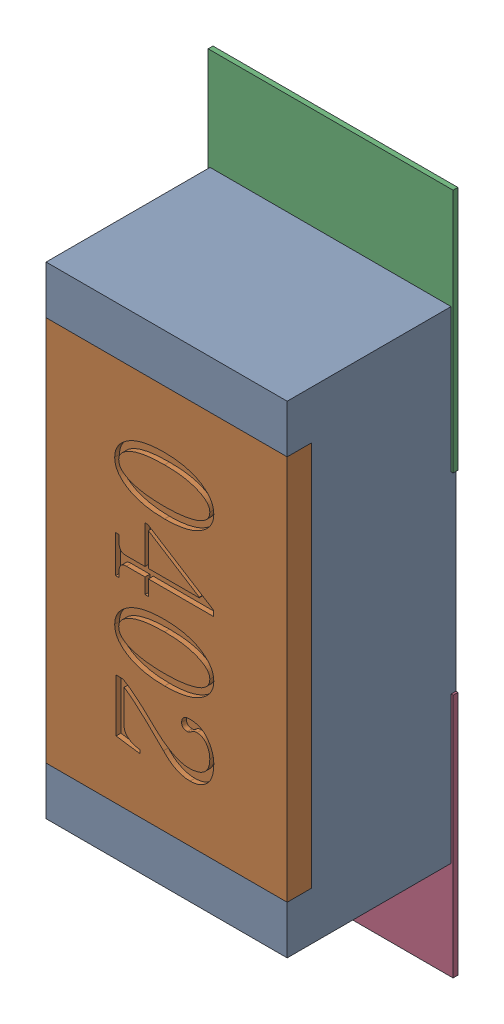
SolidWorks assembly R141, configuration Défaut. Lengths in mm.
Overall size (0.51 1.42 0.35).
5 component instances, 2 part files, 0 mates.
Components (placement in the parent):
- R0402-1: R0402 [Défaut] at (21.5899 -20.8788 0) x (0 -1 0) z (0 0 1) size (1 0.5 0.35)
- 6504207776-1: 6504207776 [Défaut] at (21.59 -20.4217 0) size (0.51 0.51 0.01)
  - Extruded-1: Extruded [Défaut] at origin size (0.51 0.51 0.01)
- 6504207776-2: 6504207776 [Défaut] at (21.59 -21.3288 0) size (0.51 0.51 0.01)
  - Extruded-1: Extruded [Défaut] at origin size (0.51 0.51 0.01)
